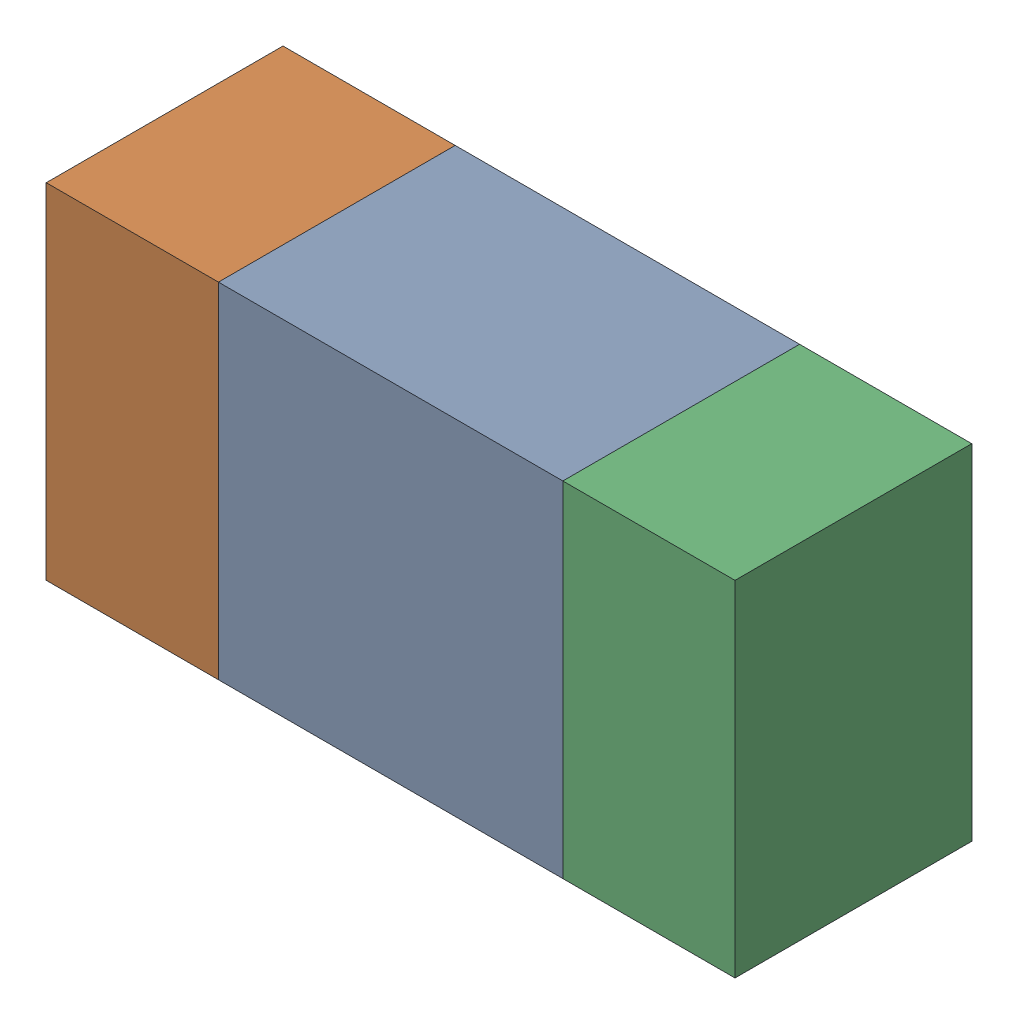
SolidWorks assembly R45, configuration ﾃﾞﾌｫﾙﾄ. Lengths in mm.
Overall size (1.6 0.8 0.55).
6 component instances, 2 part files, 0 mates.
Components (placement in the parent):
- 689261648-1: 689261648 [ﾃﾞﾌｫﾙﾄ] at (57.5 38.3999 0) size (0.8 0.8 0.55)
  - Extruded_33-1: Extruded_33 [ﾃﾞﾌｫﾙﾄ] at origin size (0.8 0.8 0.55)
- 689261512-1: 689261512 [ﾃﾞﾌｫﾙﾄ] at (56.8999 38.3999 0) size (0.4 0.8 0.55)
  - Extruded_32-1: Extruded_32 [ﾃﾞﾌｫﾙﾄ] at origin size (0.4 0.8 0.55)
- 689261512-2: 689261512 [ﾃﾞﾌｫﾙﾄ] at (58.0999 38.3999 0) size (0.4 0.8 0.55)
  - Extruded_32-1: Extruded_32 [ﾃﾞﾌｫﾙﾄ] at origin size (0.4 0.8 0.55)
